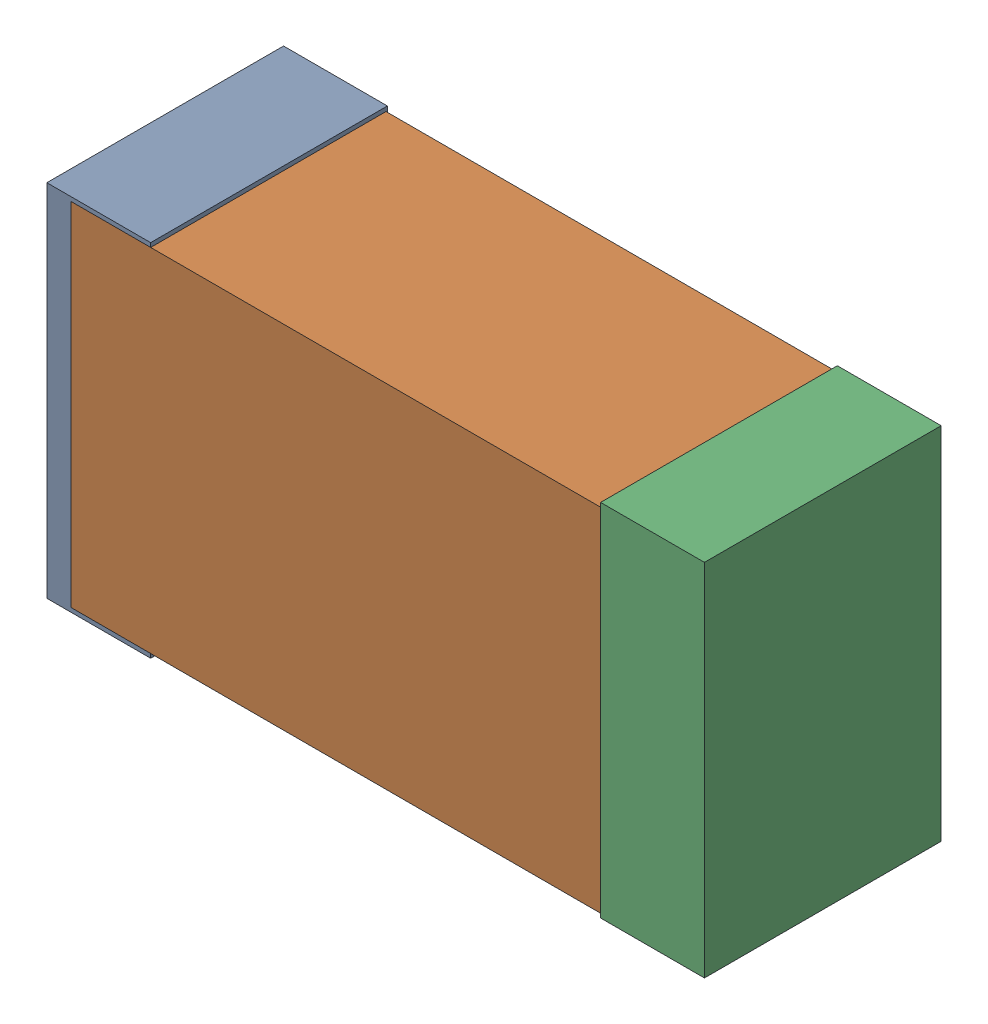
SolidWorks assembly R14, configuration Default. Lengths in mm.
Overall size (2.38 1.3 0.85).
6 component instances, 2 part files, 0 mates.
Components (placement in the parent):
- 384311232-1: 384311232 [Default] at (5.35 73.152 -1.9574) size (0.38 1.3 0.85)
  - Extruded_8-1: Extruded_8 [Default] at origin size (0.38 1.3 0.85)
- 384311360-1: 384311360 [Default] at (6.35 73.152 -1.9524) size (2.2 1.27 0.85)
  - Extruded_9-1: Extruded_9 [Default] at origin size (2.2 1.27 0.85)
- 384311232-2: 384311232 [Default] at (7.35 73.152 -1.9574) size (0.38 1.3 0.85)
  - Extruded_8-1: Extruded_8 [Default] at origin size (0.38 1.3 0.85)
